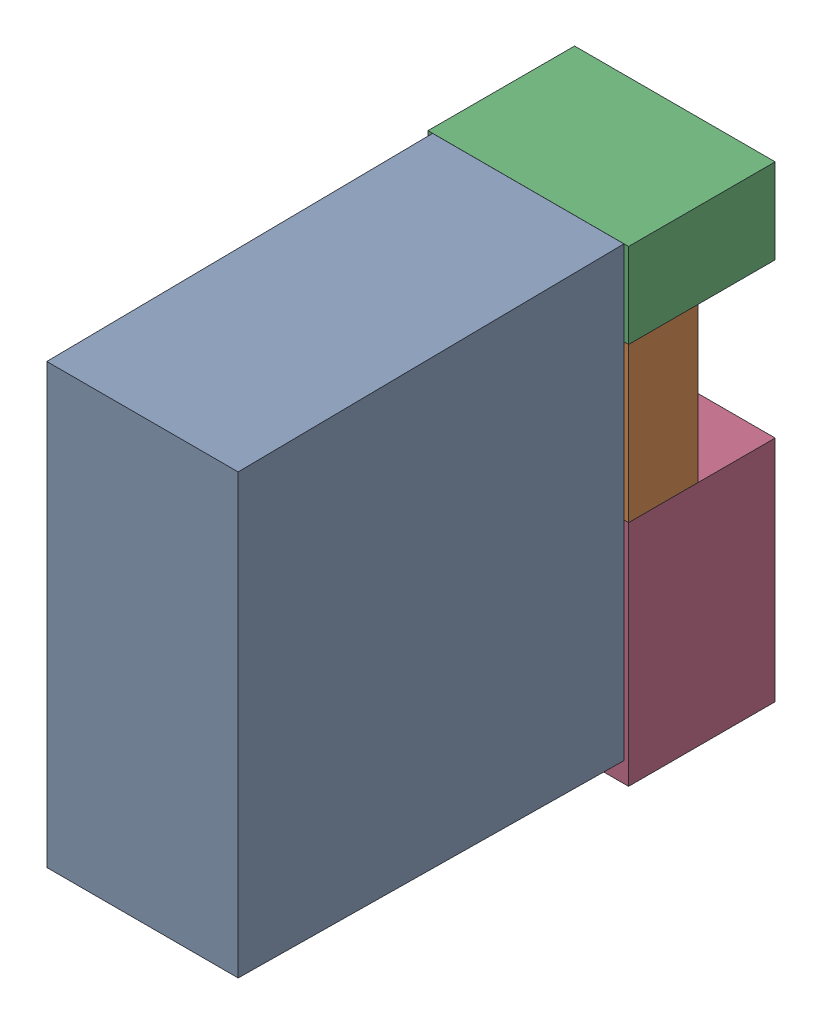
SolidWorks assembly K4, configuration Default. Lengths in mm.
Overall size (13 30.3 34.5).
7 component instances, 4 part files, 0 mates.
Components (placement in the parent):
- relais_40_61_8_006_0000-1: relais_40_61_8_006_0000 [Default] at (52.705 15.7216 9.5) x (0 1 0) z (1 0 0) size (29 30 12.4)
- 1151725064-1: 1151725064 [Default] at (52.705 34.225 5) size (13 10 4.5)
  - Extruded_3-1: Extruded_3 [Default] at origin size (13 10 4.5)
- 1151724928-1: 1151724928 [Default] at (52.705 41.975 0) size (13 5.5 9.5)
  - Extruded_2-1: Extruded_2 [Default] at origin size (13 5.5 9.5)
- 1151724792-1: 1151724792 [Default] at (52.705 21.825 0) size (13 14.8 9.5)
  - Extruded_4-1: Extruded_4 [Default] at origin size (13 14.8 9.5)
